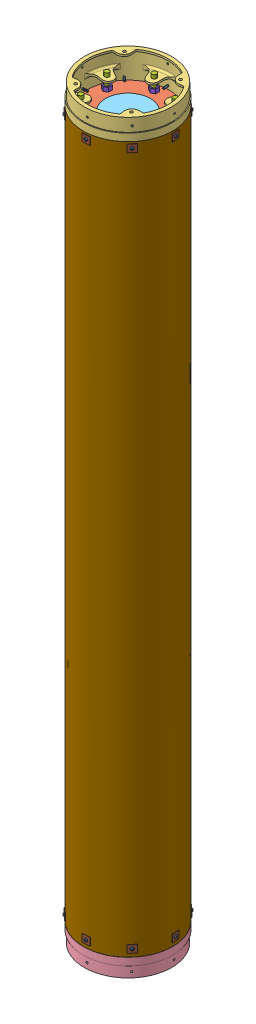
SolidWorks assembly 10005-R04_ASSEMBLY_PRESSURANT_BULK_HEAD, configuration Default. Lengths in mm.
Overall size (430.16 2546.35 430.16).
57 component instances, 11 part files, 62 mates.
Components (placement in the parent):
- 15001-R06_PRESSURANT_TANK-1: 15001-R06_PRESSURANT_TANK [Default] at origin size (284.43 2421.28 284.43)
- 15002-R02_PRESSURANT_TANK_RETAINER-1: 15002-R02_PRESSURANT_TANK_RETAINER [Default] at (132.1098 2248.7992 54.2831) x (0.750059 0 -0.661371) z (0.661371 0 0.750059) size (279.4 9.53 279.4)
- 15005-R06_PRESSURANT_TANK_BULKHEAD_TOP-1: 15005-R06_PRESSURANT_TANK_BULKHEAD_TOP [Default] at (0 2244.471 0) x (0.657316 0 -0.753615) z (0.753615 0 0.657316) size (304.8 107.95 304.8)
- 15006-R03_PRESSURANT_TANK_BULKHEAD_BOT-1: 15006-R03_PRESSURANT_TANK_BULKHEAD_BOT [Default] at (0 -193.929 0) x (0.751155 0 0.660126) z (-0.660126 0 0.751155) size (304.8 101.6 304.8)
- 15007-R05_VIBRATION_ABSORBER-1: 15007-R05_VIBRATION_ABSORBER [Default] at (0 382.2802 0) size (152.4 35.26 152.4)
- 15008-R03_LOWER_VIBRATION_ABSORBER-1: 15008-R03_LOWER_VIBRATION_ABSORBER [Default] at (0 1729.74 0) x (-0.837169 0 -0.546944) z (-0.546944 0 0.837169) size (152.4 35.26 152.4)
- 16001-R01_THREADED_ROD-1: 16001-R01_THREADED_ROD [Default] at (-108.3328 2234.9085 -36.4485) x (0.81269 0 0.582696) z (-0.582696 0 0.81269) size (15.88 76.2 15.88)
- 16001-R01_THREADED_ROD-2: 16001-R01_THREADED_ROD [Default] at (-22.601 2234.9085 -112.0432) x (0.847931 0 -0.530106) z (0.530106 0 0.847931) size (15.88 76.2 15.88)
- 16001-R01_THREADED_ROD-3: 16001-R01_THREADED_ROD [Default] at (108.3328 2234.9085 36.4485) size (15.88 76.2 15.88)
- 16001-R01_THREADED_ROD-4: 16001-R01_THREADED_ROD [Default] at (85.7318 2234.9085 -75.5947) size (15.88 76.2 15.88)
- 16001-R01_THREADED_ROD-5: 16001-R01_THREADED_ROD [Default] at (22.601 2234.9085 112.0432) size (15.88 76.2 15.88)
- 16001-R01_THREADED_ROD-6: 16001-R01_THREADED_ROD [Default] at (-85.7318 2234.9085 75.5947) size (15.88 76.2 15.88)
- 91845A325_TYPE 18-8 STAINLESS STEEL HEX NUT-1: 91845A325_TYPE 18-8 STAINLESS STEEL HEX NUT [91845A325] at (-108.3328 2241.8538 -36.4485) x (1 0 0) z (0 -1 0) size (23.81 27.5 16.67)
- 91845A325_TYPE 18-8 STAINLESS STEEL HEX NUT-2: 91845A325_TYPE 18-8 STAINLESS STEEL HEX NUT [91845A325] at (-85.7318 2241.8538 75.5947) x (1 0 0) z (0 -1 0) size (23.81 27.5 16.67)
- 91845A325_TYPE 18-8 STAINLESS STEEL HEX NUT-3: 91845A325_TYPE 18-8 STAINLESS STEEL HEX NUT [91845A325] at (-22.601 2241.8538 -112.0432) x (1 0 0) z (0 -1 0) size (23.81 27.5 16.67)
- 91845A325_TYPE 18-8 STAINLESS STEEL HEX NUT-4: 91845A325_TYPE 18-8 STAINLESS STEEL HEX NUT [91845A325] at (85.7318 2241.8538 -75.5947) x (1 0 0) z (0 -1 0) size (23.81 27.5 16.67)
- 91845A325_TYPE 18-8 STAINLESS STEEL HEX NUT-5: 91845A325_TYPE 18-8 STAINLESS STEEL HEX NUT [91845A325] at (108.3328 2241.8538 36.4485) x (1 0 0) z (0 -1 0) size (23.81 27.5 16.67)
- 91845A325_TYPE 18-8 STAINLESS STEEL HEX NUT-6: 91845A325_TYPE 18-8 STAINLESS STEEL HEX NUT [91845A325] at (22.601 2241.8538 112.0432) x (1 0 0) z (0 -1 0) size (23.81 27.5 16.67)
- 91845A325_TYPE 18-8 STAINLESS STEEL HEX NUT-7: 91845A325_TYPE 18-8 STAINLESS STEEL HEX NUT [91845A325] at (85.7318 2265.2695 -75.5947) x (1 0 0) z (0 1 0) size (23.81 27.5 16.67)
- 91845A325_TYPE 18-8 STAINLESS STEEL HEX NUT-8: 91845A325_TYPE 18-8 STAINLESS STEEL HEX NUT [91845A325] at (108.3328 2265.2695 36.4485) x (1 0 0) z (0 1 0) size (23.81 27.5 16.67)
- 91845A325_TYPE 18-8 STAINLESS STEEL HEX NUT-9: 91845A325_TYPE 18-8 STAINLESS STEEL HEX NUT [91845A325] at (-85.7318 2265.2695 75.5947) x (1 0 0) z (0 1 0) size (23.81 27.5 16.67)
- 91845A325_TYPE 18-8 STAINLESS STEEL HEX NUT-10: 91845A325_TYPE 18-8 STAINLESS STEEL HEX NUT [91845A325] at (22.601 2265.2695 112.0432) x (1 0 0) z (0 1 0) size (23.81 27.5 16.67)
- 91845A325_TYPE 18-8 STAINLESS STEEL HEX NUT-11: 91845A325_TYPE 18-8 STAINLESS STEEL HEX NUT [91845A325] at (-22.601 2265.2695 -112.0432) x (1 0 0) z (0 1 0) size (23.81 27.5 16.67)
- 91845A325_TYPE 18-8 STAINLESS STEEL HEX NUT-12: 91845A325_TYPE 18-8 STAINLESS STEEL HEX NUT [91845A325] at (-108.3328 2265.2695 -36.4485) x (1 0 0) z (0 1 0) size (23.81 27.5 16.67)
- 14008_R01_AIRFRAME_SEC2-1: 14008_R01_AIRFRAME_SEC2 [Default] at (0 2282.571 0) x (0.660126 0 -0.751155) z (0 -1 0) size (304.8 304.8 2413)
- 92949A542_18-8 SS BUTTON-HEAD SOCKET CAP SCREW-1: 92949A542_18-8 SS BUTTON-HEAD SOCKET CAP SCREW [92949A542] at (-156.6182 2263.521 10.102) x (-0.064367 0 -0.997926) z (-0.997926 0 0.064367) size (11.1 11.1 29.48)
- 14061_R01_CURVED_BOLT_MATES-1: 14061_R01_CURVED_BOLT_MATES [Default] at (0 2276.221 0) x (-0.064367 0 -0.997926) z (0.997926 0 -0.064367) size (25.4 25.4 1.72)
- 92949A542_18-8 SS BUTTON-HEAD SOCKET CAP SCREW-9: 92949A542_18-8 SS BUTTON-HEAD SOCKET CAP SCREW [92949A542] at (-103.6026 2263.521 117.889) x (-0.751155 0 -0.660126) z (-0.660126 0 0.751155) size (11.1 11.1 29.48)
- 92949A542_18-8 SS BUTTON-HEAD SOCKET CAP SCREW-10: 92949A542_18-8 SS BUTTON-HEAD SOCKET CAP SCREW [92949A542] at (10.102 2263.521 156.6182) x (-0.997926 0 0.064367) z (0.064367 0 0.997926) size (11.1 11.1 29.48)
- 92949A542_18-8 SS BUTTON-HEAD SOCKET CAP SCREW-11: 92949A542_18-8 SS BUTTON-HEAD SOCKET CAP SCREW [92949A542] at (117.889 2263.521 103.6026) x (-0.660126 0 0.751155) z (0.751155 0 0.660126) size (11.1 11.1 29.48)
- 92949A542_18-8 SS BUTTON-HEAD SOCKET CAP SCREW-12: 92949A542_18-8 SS BUTTON-HEAD SOCKET CAP SCREW [92949A542] at (156.6182 2263.521 -10.102) x (0.064367 0 0.997926) z (0.997926 0 -0.064367) size (11.1 11.1 29.48)
- 92949A542_18-8 SS BUTTON-HEAD SOCKET CAP SCREW-13: 92949A542_18-8 SS BUTTON-HEAD SOCKET CAP SCREW [92949A542] at (103.6026 2263.521 -117.889) x (0.751155 0 0.660126) z (0.660126 0 -0.751155) size (11.1 11.1 29.48)
- 92949A542_18-8 SS BUTTON-HEAD SOCKET CAP SCREW-14: 92949A542_18-8 SS BUTTON-HEAD SOCKET CAP SCREW [92949A542] at (-10.102 2263.521 -156.6182) x (0.997926 0 -0.064367) z (-0.064367 0 -0.997926) size (11.1 11.1 29.48)
- 92949A542_18-8 SS BUTTON-HEAD SOCKET CAP SCREW-15: 92949A542_18-8 SS BUTTON-HEAD SOCKET CAP SCREW [92949A542] at (-117.889 2263.521 -103.6026) x (0.660126 0 -0.751155) z (-0.751155 0 -0.660126) size (11.1 11.1 29.48)
- 14061_R01_CURVED_BOLT_MATES-2: 14061_R01_CURVED_BOLT_MATES [Default] at (0 2276.221 0) x (-0.751155 0 -0.660126) z (0.660126 0 -0.751155) size (25.4 25.4 1.72)
- 14061_R01_CURVED_BOLT_MATES-3: 14061_R01_CURVED_BOLT_MATES [Default] at (0 2276.221 0) x (-0.997926 0 0.064367) z (-0.064367 0 -0.997926) size (25.4 25.4 1.72)
- 14061_R01_CURVED_BOLT_MATES-4: 14061_R01_CURVED_BOLT_MATES [Default] at (0 2276.221 0) x (-0.660126 0 0.751155) z (-0.751155 0 -0.660126) size (25.4 25.4 1.72)
- 14061_R01_CURVED_BOLT_MATES-5: 14061_R01_CURVED_BOLT_MATES [Default] at (0 2276.221 0) x (0.064367 0 0.997926) z (-0.997926 0 0.064367) size (25.4 25.4 1.72)
- 14061_R01_CURVED_BOLT_MATES-6: 14061_R01_CURVED_BOLT_MATES [Default] at (0 2276.221 0) x (0.751155 0 0.660126) z (-0.660126 0 0.751155) size (25.4 25.4 1.72)
- 14061_R01_CURVED_BOLT_MATES-7: 14061_R01_CURVED_BOLT_MATES [Default] at (0 2276.221 0) x (0.997926 0 -0.064367) z (0.064367 0 0.997926) size (25.4 25.4 1.72)
- 14061_R01_CURVED_BOLT_MATES-8: 14061_R01_CURVED_BOLT_MATES [Default] at (0 2276.221 0) x (0.660126 0 -0.751155) z (0.751155 0 0.660126) size (25.4 25.4 1.72)
- 92949A542_18-8 SS BUTTON-HEAD SOCKET CAP SCREW-16: 92949A542_18-8 SS BUTTON-HEAD SOCKET CAP SCREW [92949A542] at (-156.6182 -105.029 10.102) x (-0.064367 0 -0.997926) z (-0.997926 0 0.064367) size (11.1 11.1 29.48)
- 14061_R01_CURVED_BOLT_MATES-9: 14061_R01_CURVED_BOLT_MATES [Default] at (0 -117.729 0) x (0.064367 0 0.997926) z (0.997926 0 -0.064367) size (25.4 25.4 1.72)
- 92949A542_18-8 SS BUTTON-HEAD SOCKET CAP SCREW-17: 92949A542_18-8 SS BUTTON-HEAD SOCKET CAP SCREW [92949A542] at (-103.6026 -105.029 117.889) x (0.751155 0 0.660126) z (-0.660126 0 0.751155) size (11.1 11.1 29.48)
- 92949A542_18-8 SS BUTTON-HEAD SOCKET CAP SCREW-18: 92949A542_18-8 SS BUTTON-HEAD SOCKET CAP SCREW [92949A542] at (10.102 -105.029 156.6182) x (-0.997926 0 0.064367) z (0.064367 0 0.997926) size (11.1 11.1 29.48)
- 92949A542_18-8 SS BUTTON-HEAD SOCKET CAP SCREW-19: 92949A542_18-8 SS BUTTON-HEAD SOCKET CAP SCREW [92949A542] at (117.889 -105.029 103.6026) x (-0.660126 0 0.751155) z (0.751155 0 0.660126) size (11.1 11.1 29.48)
- 92949A542_18-8 SS BUTTON-HEAD SOCKET CAP SCREW-20: 92949A542_18-8 SS BUTTON-HEAD SOCKET CAP SCREW [92949A542] at (156.6182 -105.029 -10.102) x (0.064367 0 0.997926) z (0.997926 0 -0.064367) size (11.1 11.1 29.48)
- 92949A542_18-8 SS BUTTON-HEAD SOCKET CAP SCREW-21: 92949A542_18-8 SS BUTTON-HEAD SOCKET CAP SCREW [92949A542] at (103.6026 -105.029 -117.889) x (-0.751155 0 -0.660126) z (0.660126 0 -0.751155) size (11.1 11.1 29.48)
- 92949A542_18-8 SS BUTTON-HEAD SOCKET CAP SCREW-22: 92949A542_18-8 SS BUTTON-HEAD SOCKET CAP SCREW [92949A542] at (-10.102 -105.029 -156.6182) x (0.997926 0 -0.064367) z (-0.064367 0 -0.997926) size (11.1 11.1 29.48)
- 92949A542_18-8 SS BUTTON-HEAD SOCKET CAP SCREW-23: 92949A542_18-8 SS BUTTON-HEAD SOCKET CAP SCREW [92949A542] at (-117.889 -105.029 -103.6026) x (0.660126 0 -0.751155) z (-0.751155 0 -0.660126) size (11.1 11.1 29.48)
- 14061_R01_CURVED_BOLT_MATES-10: 14061_R01_CURVED_BOLT_MATES [Default] at (0 -117.729 0) x (0.751155 0 0.660126) z (0.660126 0 -0.751155) size (25.4 25.4 1.72)
- 14061_R01_CURVED_BOLT_MATES-11: 14061_R01_CURVED_BOLT_MATES [Default] at (0 -117.729 0) x (0.997926 0 -0.064367) z (-0.064367 0 -0.997926) size (25.4 25.4 1.72)
- 14061_R01_CURVED_BOLT_MATES-12: 14061_R01_CURVED_BOLT_MATES [Default] at (0 -117.729 0) x (0.660126 0 -0.751155) z (-0.751155 0 -0.660126) size (25.4 25.4 1.72)
- 14061_R01_CURVED_BOLT_MATES-13: 14061_R01_CURVED_BOLT_MATES [Default] at (0 -117.729 0) x (-0.064367 0 -0.997926) z (-0.997926 0 0.064367) size (25.4 25.4 1.72)
- 14061_R01_CURVED_BOLT_MATES-14: 14061_R01_CURVED_BOLT_MATES [Default] at (0 -117.729 0) x (-0.751155 0 -0.660126) z (-0.660126 0 0.751155) size (25.4 25.4 1.72)
- 14061_R01_CURVED_BOLT_MATES-15: 14061_R01_CURVED_BOLT_MATES [Default] at (0 -117.729 0) x (-0.997926 0 0.064367) z (0.064367 0 0.997926) size (25.4 25.4 1.72)
- 14061_R01_CURVED_BOLT_MATES-16: 14061_R01_CURVED_BOLT_MATES [Default] at (0 -117.729 0) x (-0.660126 0 0.751155) z (0.751155 0 0.660126) size (25.4 25.4 1.72)
Mates (geometry in assembly coordinates):
- Coincident2: coincident: plane of 15001-R06_PRESSURANT_TANK-1 through (0 0 0) normal (0 0 1); plane of assembly through (0 0 0) normal (0 0 1)
- Coincident3: coincident: plane of 15001-R06_PRESSURANT_TANK-1 through (0 0 0) normal (0 1 0); plane of assembly through (0 0 0) normal (0 1 0)
- Coincident4: coincident: plane of 15001-R06_PRESSURANT_TANK-1 through (0 0 0) normal (1 0 0); plane of assembly through (0 0 0) normal (1 0 0)
- Concentric1: concentric: sphere of 15001-R06_PRESSURANT_TANK-1; sphere of 15007-R05_VIBRATION_ABSORBER-1
- Concentric2: concentric: cylinder of 15002-R02_PRESSURANT_TANK_RETAINER-1 through (0 2258.3242 0) axis (0 -1 0) radius 69.85; cylinder of 15007-R05_VIBRATION_ABSORBER-1 through (0 432.6382 0) axis (0 1 0) radius 69.85
- Coincident5: coincident: plane of 15002-R02_PRESSURANT_TANK_RETAINER-1 through (0 2248.7992 0) normal (0 -1 0); plane of 15007-R05_VIBRATION_ABSORBER-1 through (-69.85 2248.7992 0) normal (0 1 0)
- Coincident6: coincident: plane of 15006-R03_PRESSURANT_TANK_BULKHEAD_BOT-1 through (0 -146.304 0) normal (0 -1 0); plane of 15008-R03_LOWER_VIBRATION_ABSORBER-1 through (58.4763 -146.304 38.204) normal (0 1 0)
- Concentric4: concentric: cylinder of 15006-R03_PRESSURANT_TANK_BULKHEAD_BOT-1 through (0 -193.929 0) axis (0 1 0) radius 69.85; cylinder of 15008-R03_LOWER_VIBRATION_ABSORBER-1 through (0 1679.382 0) axis (0 -1 0) radius 69.85
- Concentric5: concentric: sphere of 15001-R06_PRESSURANT_TANK-1; sphere of 15008-R03_LOWER_VIBRATION_ABSORBER-1
- Concentric6: concentric: cylinder of 15002-R02_PRESSURANT_TANK_RETAINER-1 through (-108.3328 2248.7982 -36.4485) axis (0 1 0) radius 7.9375; cylinder of 16001-R01_THREADED_ROD-1 through (-108.3328 2311.1085 -36.4485) axis (0 -1 0) radius 7.9375
- Concentric7: concentric: cylinder of 15002-R02_PRESSURANT_TANK_RETAINER-1 through (-22.601 2248.7982 -112.0432) axis (0 1 0) radius 7.9375; cylinder of 16001-R01_THREADED_ROD-2 through (-22.601 2311.1085 -112.0432) axis (0 -1 0) radius 7.9375
- Concentric8: concentric: cylinder of 15002-R02_PRESSURANT_TANK_RETAINER-1 through (-85.7318 2248.7982 75.5947) axis (0 1 0) radius 7.9375; cylinder of 16001-R01_THREADED_ROD-6 through (-85.7318 2311.1085 75.5947) axis (0 -1 0) radius 7.9375
- Concentric9: concentric: cylinder of 15002-R02_PRESSURANT_TANK_RETAINER-1 through (22.601 2248.7982 112.0432) axis (0 1 0) radius 7.9375; cylinder of 16001-R01_THREADED_ROD-5 through (22.601 2311.1085 112.0432) axis (0 -1 0) radius 7.9375
- Concentric10: concentric: cylinder of 15002-R02_PRESSURANT_TANK_RETAINER-1 through (85.7318 2248.7982 -75.5947) axis (0 1 0) radius 7.9375; cylinder of 16001-R01_THREADED_ROD-4 through (85.7318 2311.1085 -75.5947) axis (0 -1 0) radius 7.9375
- Concentric11: concentric: cylinder of 15002-R02_PRESSURANT_TANK_RETAINER-1 through (108.3328 2248.7982 36.4485) axis (0 1 0) radius 7.9375; cylinder of 16001-R01_THREADED_ROD-3 through (108.3328 2311.1085 36.4485) axis (0 -1 0) radius 7.9375
- Concentric12: concentric: cylinder of 16001-R01_THREADED_ROD-1 through (-108.3328 2311.1085 -36.4485) axis (0 -1 0) radius 7.9375; cylinder of 91845A325_TYPE 18-8 STAINLESS STEEL HEX NUT-1 through (-108.3328 2234.9085 -36.4485) axis (0 1 0) radius 7.9375
- Coincident7: coincident: plane of 15002-R02_PRESSURANT_TANK_RETAINER-1 through (0 2248.7992 0) normal (0 -1 0); plane of 91845A325_TYPE 18-8 STAINLESS STEEL HEX NUT-1 through (-120.239 2248.7992 -29.5745) normal (0 1 0)
- Coincident8: coincident: plane of 16001-R01_THREADED_ROD-1 through (-108.3328 2234.9085 -36.4485) normal (0 -1 0); plane of 91845A325_TYPE 18-8 STAINLESS STEEL HEX NUT-1 through (-120.239 2234.9085 -29.5745) normal (0 -1 0)
- Concentric13: concentric: cylinder of 16001-R01_THREADED_ROD-6 through (-85.7318 2311.1085 75.5947) axis (0 -1 0) radius 7.9375; cylinder of 91845A325_TYPE 18-8 STAINLESS STEEL HEX NUT-2 through (-85.7318 2234.9085 75.5947) axis (0 1 0) radius 7.9375
- Coincident10: coincident: plane of 15002-R02_PRESSURANT_TANK_RETAINER-1 through (0 2248.7992 0) normal (0 -1 0); plane of 91845A325_TYPE 18-8 STAINLESS STEEL HEX NUT-2 through (-97.638 2248.7992 82.4688) normal (0 1 0)
- Coincident11: coincident: plane of 16001-R01_THREADED_ROD-6 through (-85.7318 2234.9085 75.5947) normal (0 -1 0); plane of 91845A325_TYPE 18-8 STAINLESS STEEL HEX NUT-2 through (-97.638 2234.9085 82.4688) normal (0 -1 0)
- Concentric14: concentric: cylinder of 16001-R01_THREADED_ROD-2 through (-22.601 2311.1085 -112.0432) axis (0 -1 0) radius 7.9375; cylinder of 91845A325_TYPE 18-8 STAINLESS STEEL HEX NUT-3 through (-22.601 2234.9085 -112.0432) axis (0 1 0) radius 7.9375
- Coincident12: coincident: plane of 15002-R02_PRESSURANT_TANK_RETAINER-1 through (0 2248.7992 0) normal (0 -1 0); plane of 91845A325_TYPE 18-8 STAINLESS STEEL HEX NUT-3 through (-34.5073 2248.7992 -105.1691) normal (0 1 0)
- Coincident13: coincident: plane of 16001-R01_THREADED_ROD-2 through (-22.601 2234.9085 -112.0432) normal (0 -1 0); plane of 91845A325_TYPE 18-8 STAINLESS STEEL HEX NUT-3 through (-34.5073 2234.9085 -105.1691) normal (0 -1 0)
- Concentric15: concentric: cylinder of 16001-R01_THREADED_ROD-4 through (85.7318 2311.1085 -75.5947) axis (0 -1 0) radius 7.9375; cylinder of 91845A325_TYPE 18-8 STAINLESS STEEL HEX NUT-4 through (85.7318 2234.9085 -75.5947) axis (0 1 0) radius 7.9375
- Coincident14: coincident: plane of 15002-R02_PRESSURANT_TANK_RETAINER-1 through (0 2248.7992 0) normal (0 -1 0); plane of 91845A325_TYPE 18-8 STAINLESS STEEL HEX NUT-4 through (73.8255 2248.7992 -68.7206) normal (0 1 0)
- Coincident15: coincident: circle of 16001-R01_THREADED_ROD-4; plane of 91845A325_TYPE 18-8 STAINLESS STEEL HEX NUT-4 through (73.8255 2234.9085 -68.7206) normal (0 -1 0)
- Concentric16: concentric: cylinder of 16001-R01_THREADED_ROD-3 through (108.3328 2311.1085 36.4485) axis (0 -1 0) radius 7.9375; cylinder of 91845A325_TYPE 18-8 STAINLESS STEEL HEX NUT-5 through (108.3328 2234.9085 36.4485) axis (0 1 0) radius 7.9375
- Coincident16: coincident: plane of 15002-R02_PRESSURANT_TANK_RETAINER-1 through (0 2248.7992 0) normal (0 -1 0); plane of 91845A325_TYPE 18-8 STAINLESS STEEL HEX NUT-5 through (96.4265 2248.7992 43.3226) normal (0 1 0)
- Coincident17: coincident: plane of 16001-R01_THREADED_ROD-3 through (108.3328 2234.9085 36.4485) normal (0 -1 0); plane of 91845A325_TYPE 18-8 STAINLESS STEEL HEX NUT-5 through (96.4265 2234.9085 43.3226) normal (0 -1 0)
- Concentric17: concentric: cylinder of 16001-R01_THREADED_ROD-5 through (22.601 2311.1085 112.0432) axis (0 -1 0) radius 7.9375; cylinder of 91845A325_TYPE 18-8 STAINLESS STEEL HEX NUT-6 through (22.601 2234.9085 112.0432) axis (0 1 0) radius 7.9375
- Coincident18: coincident: plane of 15002-R02_PRESSURANT_TANK_RETAINER-1 through (0 2248.7992 0) normal (0 -1 0); plane of 91845A325_TYPE 18-8 STAINLESS STEEL HEX NUT-6 through (10.6948 2248.7992 118.9173) normal (0 1 0)
- Coincident19: coincident: plane of 16001-R01_THREADED_ROD-5 through (22.601 2234.9085 112.0432) normal (0 -1 0); plane of 91845A325_TYPE 18-8 STAINLESS STEEL HEX NUT-6 through (10.6948 2234.9085 118.9173) normal (0 -1 0)
- Coincident20: coincident: plane of 15002-R02_PRESSURANT_TANK_RETAINER-1 through (0 2258.3242 0) normal (0 1 0); plane of 91845A325_TYPE 18-8 STAINLESS STEEL HEX NUT-11 through (-34.5073 2258.3242 -118.9173) normal (0 -1 0)
- Coincident21: coincident: plane of 15002-R02_PRESSURANT_TANK_RETAINER-1 through (0 2258.3242 0) normal (0 1 0); plane of 91845A325_TYPE 18-8 STAINLESS STEEL HEX NUT-12 through (-120.239 2258.3242 -43.3226) normal (0 -1 0)
- Coincident22: coincident: plane of 15002-R02_PRESSURANT_TANK_RETAINER-1 through (0 2258.3242 0) normal (0 1 0); plane of 91845A325_TYPE 18-8 STAINLESS STEEL HEX NUT-7 through (73.8255 2258.3242 -82.4688) normal (0 -1 0)
- Coincident23: coincident: plane of 15002-R02_PRESSURANT_TANK_RETAINER-1 through (0 2258.3242 0) normal (0 1 0); plane of 91845A325_TYPE 18-8 STAINLESS STEEL HEX NUT-8 through (96.4265 2258.3242 29.5745) normal (0 -1 0)
- Coincident24: coincident: plane of 15002-R02_PRESSURANT_TANK_RETAINER-1 through (0 2258.3242 0) normal (0 1 0); plane of 91845A325_TYPE 18-8 STAINLESS STEEL HEX NUT-9 through (-97.638 2258.3242 68.7206) normal (0 -1 0)
- Coincident25: coincident: plane of 15002-R02_PRESSURANT_TANK_RETAINER-1 through (0 2258.3242 0) normal (0 1 0); plane of 91845A325_TYPE 18-8 STAINLESS STEEL HEX NUT-10 through (10.6948 2258.3242 105.1691) normal (0 -1 0)
- Concentric18: concentric: cylinder of 16001-R01_THREADED_ROD-2 through (-22.601 2311.1085 -112.0432) axis (0 -1 0) radius 7.9375; cylinder of 91845A325_TYPE 18-8 STAINLESS STEEL HEX NUT-11 through (-22.601 2272.2148 -112.0432) axis (0 -1 0) radius 7.9375
- Concentric19: concentric: cylinder of 16001-R01_THREADED_ROD-1 through (-108.3328 2311.1085 -36.4485) axis (0 -1 0) radius 7.9375; cylinder of 91845A325_TYPE 18-8 STAINLESS STEEL HEX NUT-12 through (-108.3328 2272.2148 -36.4485) axis (0 -1 0) radius 7.9375
- Concentric20: concentric: cylinder of 16001-R01_THREADED_ROD-4 through (85.7318 2311.1085 -75.5947) axis (0 -1 0) radius 7.9375; cylinder of 91845A325_TYPE 18-8 STAINLESS STEEL HEX NUT-7 through (85.7318 2272.2148 -75.5947) axis (0 -1 0) radius 7.9375
- Concentric21: concentric: cylinder of 16001-R01_THREADED_ROD-3 through (108.3328 2311.1085 36.4485) axis (0 -1 0) radius 7.9375; cylinder of 91845A325_TYPE 18-8 STAINLESS STEEL HEX NUT-8 through (108.3328 2272.2148 36.4485) axis (0 -1 0) radius 7.9375
- Concentric22: concentric: cylinder of 16001-R01_THREADED_ROD-6 through (-85.7318 2311.1085 75.5947) axis (0 -1 0) radius 7.9375; cylinder of 91845A325_TYPE 18-8 STAINLESS STEEL HEX NUT-9 through (-85.7318 2272.2148 75.5947) axis (0 -1 0) radius 7.9375
- Concentric23: concentric: cylinder of 16001-R01_THREADED_ROD-5 through (22.601 2311.1085 112.0432) axis (0 -1 0) radius 7.9375; cylinder of 91845A325_TYPE 18-8 STAINLESS STEEL HEX NUT-10 through (22.601 2272.2148 112.0432) axis (0 -1 0) radius 7.9375
- Concentric24: concentric: cylinder of 15005-R06_PRESSURANT_TANK_BULKHEAD_TOP-1 through (85.7318 2298.446 -75.5947) axis (0 1 0) radius 7.9375; cylinder of 16001-R01_THREADED_ROD-4 through (85.7318 2311.1085 -75.5947) axis (0 -1 0) radius 7.9375
- Concentric25: concentric: cylinder of 15005-R06_PRESSURANT_TANK_BULKHEAD_TOP-1 through (108.3328 2298.446 36.4485) axis (0 1 0) radius 7.9375; cylinder of 16001-R01_THREADED_ROD-3 through (108.3328 2311.1085 36.4485) axis (0 -1 0) radius 7.9375
- Concentric26: concentric: cylinder of 15005-R06_PRESSURANT_TANK_BULKHEAD_TOP-1 through (22.601 2298.446 112.0432) axis (0 1 0) radius 7.9375; cylinder of 16001-R01_THREADED_ROD-5 through (22.601 2311.1085 112.0432) axis (0 -1 0) radius 7.9375
- Concentric27: concentric: cylinder of 15005-R06_PRESSURANT_TANK_BULKHEAD_TOP-1 through (-22.601 2298.446 -112.0432) axis (0 1 0) radius 7.9375; cylinder of 16001-R01_THREADED_ROD-2 through (-22.601 2311.1085 -112.0432) axis (0 -1 0) radius 7.9375
- Concentric28: concentric: cylinder of 15005-R06_PRESSURANT_TANK_BULKHEAD_TOP-1 through (-85.7318 2298.446 75.5947) axis (0 1 0) radius 7.9375; cylinder of 16001-R01_THREADED_ROD-6 through (-85.7318 2311.1085 75.5947) axis (0 -1 0) radius 7.9375
- Concentric29: concentric: cylinder of 15005-R06_PRESSURANT_TANK_BULKHEAD_TOP-1 through (-108.3328 2298.446 -36.4485) axis (0 1 0) radius 7.9375; cylinder of 16001-R01_THREADED_ROD-1 through (-108.3328 2311.1085 -36.4485) axis (0 -1 0) radius 7.9375
- Coincident26: coincident: plane of 15005-R06_PRESSURANT_TANK_BULKHEAD_TOP-1 through (0 2282.571 0) normal (0 -1 0); plane of 14008_R01_AIRFRAME_SEC2-1 through (0 2282.571 0) normal (0 1 0)
- Concentric30: concentric: cylinder of 15005-R06_PRESSURANT_TANK_BULKHEAD_TOP-1 through (0 2282.571 0) axis (0 -1 0) radius 149.225; cylinder of 14008_R01_AIRFRAME_SEC2-1 through (0 2282.571 0) axis (0 -1 0) radius 149.225
- Parallel1: parallel: cylinder of 15005-R06_PRESSURANT_TANK_BULKHEAD_TOP-1 through (-9.6052 2263.5234 -148.9156) axis (-0.064367 0 -0.997926) radius 3.2639; cylinder of 14008_R01_AIRFRAME_SEC2-1 through (-12.2619 2263.521 -190.105) axis (0.064367 0 0.997926) radius 3.175
- Coincident27: coincident: plane of 15006-R03_PRESSURANT_TANK_BULKHEAD_BOT-1 through (0 -130.429 0) normal (0 1 0); plane of 14008_R01_AIRFRAME_SEC2-1 through (0 -130.429 0) normal (0 -1 0)
- Concentric32: concentric: cylinder of 15006-R03_PRESSURANT_TANK_BULKHEAD_BOT-1 through (98.5073 -111.379 -112.0911) axis (0.660126 0 -0.751155) radius 3.2639; cylinder of 14008_R01_AIRFRAME_SEC2-1 through (178.7384 -111.379 -203.3857) axis (-0.660126 0 0.751155) radius 3.175
- Coincident30: coincident: cylinder of 14008_R01_AIRFRAME_SEC2-1 through (-190.105 2263.521 12.2619) axis (0.997926 0 -0.064367) radius 3.175; circle of 92949A542_18-8 SS BUTTON-HEAD SOCKET CAP SCREW-1
- Concentric34: concentric: cylinder of 14008_R01_AIRFRAME_SEC2-1 through (-190.105 2263.521 12.2619) axis (0.997926 0 -0.064367) radius 3.175; circle of 14061_R01_CURVED_BOLT_MATES-1
- Parallel3: parallel: plane of 14061_R01_CURVED_BOLT_MATES-1 through (0 2276.221 0) normal (0 1 0); plane of assembly through (0 0 0) normal (0 1 0)
- Tangent3: tangent: cylinder of 14008_R01_AIRFRAME_SEC2-1 through (0 -130.429 0) axis (0 1 0) radius 152.4; cylinder of 14061_R01_CURVED_BOLT_MATES-1 through (0 2250.821 0) axis (0 1 0) radius 152.4
- Coincident33: coincident: plane of 92949A542_18-8 SS BUTTON-HEAD SOCKET CAP SCREW-1 through (-153.2723 2269.0709 9.8862) normal (0.997926 0 -0.064367); plane of 14061_R01_CURVED_BOLT_MATES-1 through (-152.4549 2250.821 22.5598) normal (-0.997926 0 0.064367)
- Parallel4: parallel: plane of 92949A542_18-8 SS BUTTON-HEAD SOCKET CAP SCREW-1 through (-156.6182 2263.521 10.102) normal (0 -1 0); plane of assembly through (0 0 0) normal (0 1 0)
